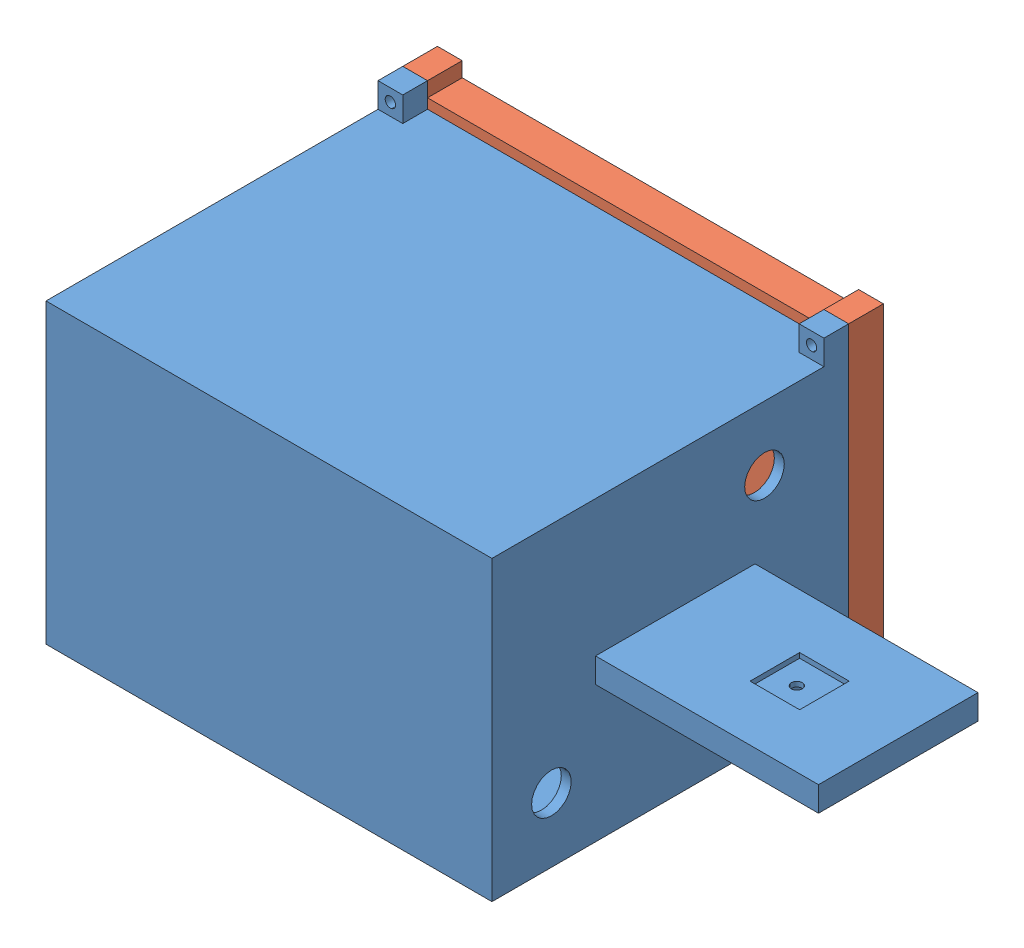
SolidWorks assembly 組合件1, configuration 預設. Lengths in mm.
Overall size (146.5 70 79).
2 component instances, 2 part files, 5 mates.
Components (placement in the parent):
- 7_20fishbody_vertical_4_2-1: 7_20fishbody_vertical_4_2 [預設] at (0.4376 -2.0373 146.5018) size (146.5 70 72)
- fish_lid_vertical5-1: fish_lid_vertical5 [預設] at (9.0154 -14.4287 136.5018) size (90 70 7)
Mates (geometry in assembly coordinates):
- 同軸心1: concentric: cylinder of 7_20fishbody_vertical_4_2-1 through (-72.5713 -38.9474 151.5018) axis (0 0 -1) radius 1.05; cylinder of fish_lid_vertical5-1 through (-72.5713 -38.9474 167.0757) axis (0 0 -1) radius 1.05
- 同軸心2: concentric: cylinder of 7_20fishbody_vertical_4_2-1 through (12.4287 -38.9474 151.5018) axis (0 0 -1) radius 1.05; cylinder of fish_lid_vertical5-1 through (12.4287 -38.9474 167.0757) axis (0 0 -1) radius 1.05
- 同軸心3: concentric: cylinder of 7_20fishbody_vertical_4_2-1 through (-72.5713 26.0526 151.5018) axis (0 0 -1) radius 1.05; cylinder of fish_lid_vertical5-1 through (-72.5713 26.0526 167.0757) axis (0 0 -1) radius 1.05
- 同軸心4: concentric: cylinder of 7_20fishbody_vertical_4_2-1 through (12.4287 26.0526 151.5018) axis (0 0 -1) radius 1.05; cylinder of fish_lid_vertical5-1 through (12.4287 26.0526 167.0757) axis (0 0 -1) radius 1.05
- 重合/共線/共點3: coincident: plane of 7_20fishbody_vertical_4_2-1 through (0.4376 -2.0373 146.5018) normal (0 0 -1); plane of fish_lid_vertical5-1 through (9.0154 -14.4287 146.5018) normal (0 0 1)
